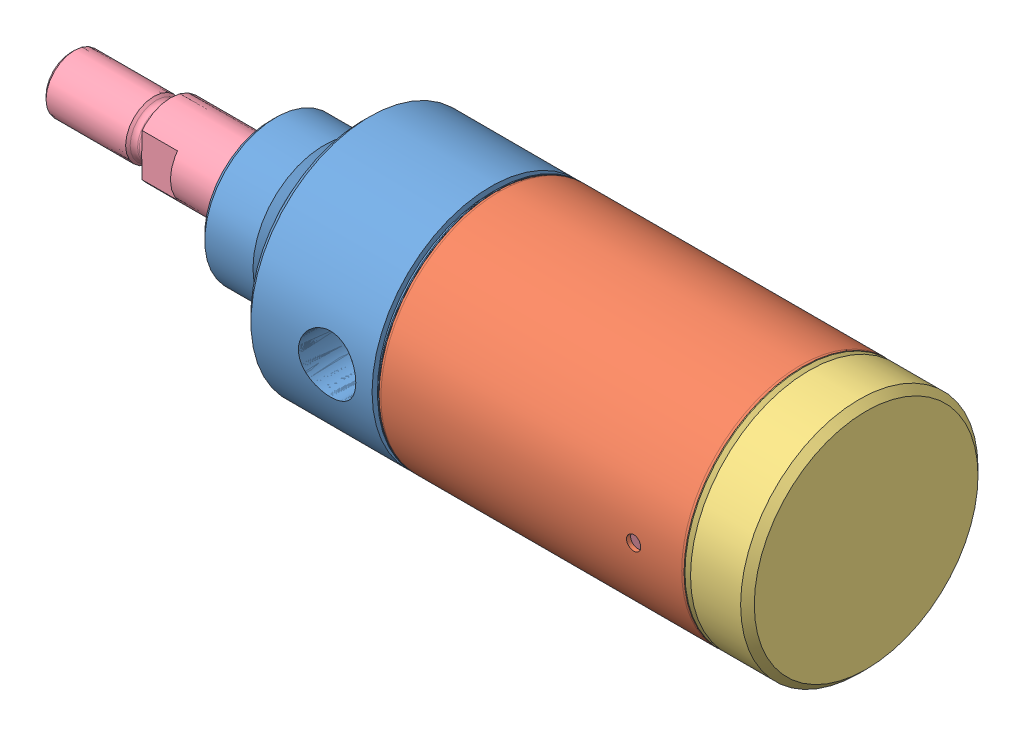
SolidWorks assembly Assem3, configuration Default. Lengths in mm.
Overall size (177.42 52.97 52.97).
5 component instances, 5 part files, 11 mates.
Components (placement in the parent):
- 310_5-RC0000_0_dummy-1: 310_5-RC0000_0_dummy [Default] at origin
- 31R000-0_5_rod_guide-1: 31R000-0_5_rod_guide [Default] at origin size (58.72 52.97 52.97)
- 31R-2_7153C-1: 31R-2_7153C [Default] at (50.2539 0 0) size (70.87 52.97 52.97)
- 31R0000_rear_head-1: 31R0000_rear_head [Default] at (112.3442 0 0) size (20.62 52.97 52.97)
- C-310_5-R0_rod-1: C-310_5-R0_rod [Default] at (-12.7 0 0) size (144.09 51.04 51.04)
Mates (geometry in assembly coordinates):
- Distance2: distance = 0 mm aligned: plane of 31R000-0_5_rod_guide-1 through (0 0 0) normal (1 0 0); plane of 310_5-RC0000_0_dummy-1 through (0 0 0) normal (1 0 0)
- Coincident1: coincident aligned: line of 310_5-RC0000_0_dummy-1 through (80.9 0 0) axis (-1 0 0); line of 31R000-0_5_rod_guide-1 through (80.9 0 0) axis (-1 0 0)
- Angle3: planar angle = 0 rad aligned: plane of 31R000-0_5_rod_guide-1 through (0 0 0) normal (0 0 -1); plane of 310_5-RC0000_0_dummy-1 through (0 0 0) normal (0 0 -1)
- Distance4: distance = 0 mm aligned: plane of 31R-2_7153C-1 through (50.2539 0 0) normal (1 0 0); plane of 31R000-0_5_rod_guide-1 through (50.2539 0 0) normal (1 0 0)
- Coincident2: coincident aligned: line of 31R000-0_5_rod_guide-1 through (80.9 0 0) axis (-1 0 0); line of 31R-2_7153C-1 through (131.1539 0 0) axis (-1 0 0)
- Angle6: planar angle = 0 rad aligned: plane of 31R-2_7153C-1 through (50.2539 0 0) normal (0 0 -1); plane of 31R000-0_5_rod_guide-1 through (0 0 0) normal (0 0 -1)
- Distance6: distance = 0 mm aligned: plane of 31R0000_rear_head-1 through (119.2149 0 0) normal (1 0 0); plane of 31R-2_7153C-1 through (119.2149 0 0) normal (1 0 0)
- Coincident3: coincident aligned: line of 31R-2_7153C-1 through (131.1539 0 0) axis (-1 0 0); line of 31R0000_rear_head-1 through (193.2442 0 0) axis (-1 0 0)
- Angle9: planar angle = 0 rad aligned: plane of 31R0000_rear_head-1 through (112.3442 0 0) normal (0 0 -1); plane of 31R-2_7153C-1 through (50.2539 0 0) normal (0 0 -1)
- LimitDistance2: limit distance = 0 mm aligned: plane of C-310_5-R0_rod-1 through (-12.7 0 0) normal (1 0 0); plane of 31R000-0_5_rod_guide-1 through (-12.7 0 0) normal (1 0 0)
- Coincident4: coincident aligned: line of 31R000-0_5_rod_guide-1 through (80.9 0 0) axis (-1 0 0); line of C-310_5-R0_rod-1 through (68.2 0 0) axis (-1 0 0)
